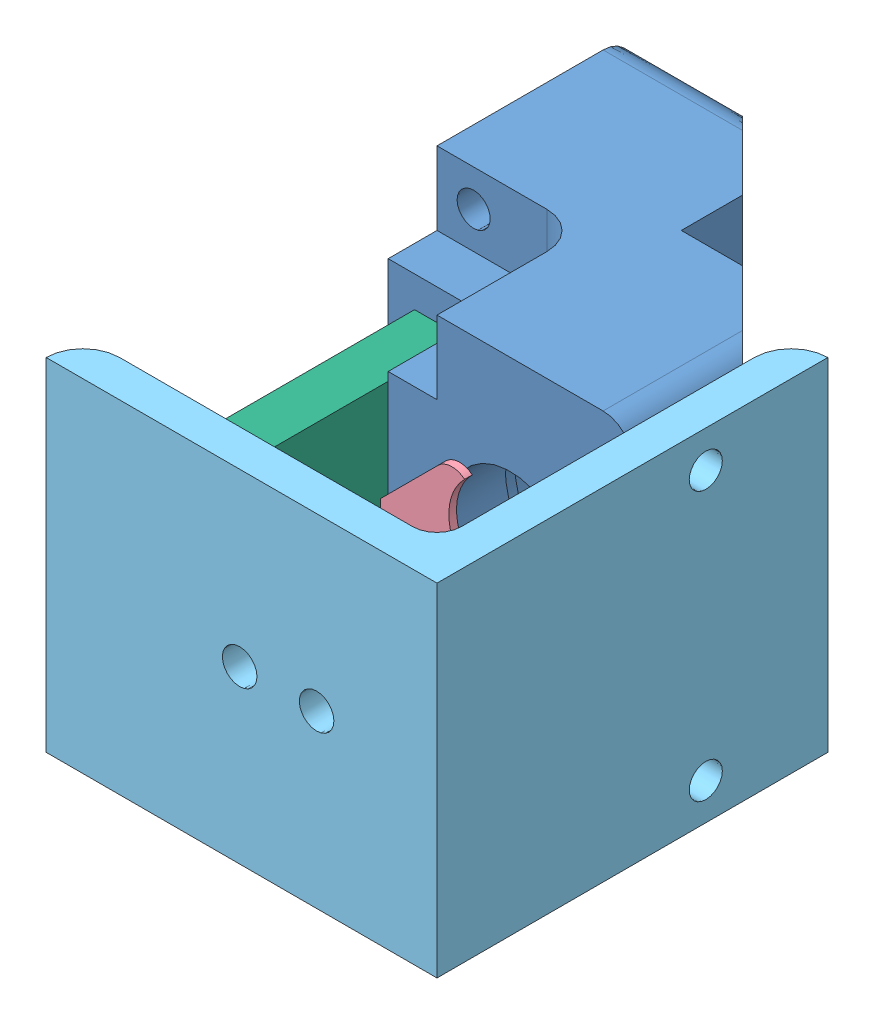
SolidWorks assembly Acceptance Test Adapter, configuration Default. Lengths in mm.
Overall size (87.75 59.75 82.98).
12 component instances, 7 part files, 7 mates.
Components (placement in the parent):
- Subtractive_Thruster Block2-1: Subtractive_Thruster Block2 [Default] at origin size (82.98 59.75 82.98)
  - Subtractive Manifold_V2-1: Subtractive Manifold_V2 [Default] at origin size (44.45 44.45 44.45)
  - C15_212EP10FF_000-1: C15_212EP10FF_000 [Default] at (-7.747 23.8125 -3.175) x (0 -0.840256 0.54219) z (0 -0.54219 -0.840256) size (15 56.18 15)
  - Generic_8-32-1: Generic_8-32 [91251A194] at (-22.1328 15.8201 4.8174) x (0 0 1) z (-1 0 0) size (6.86 6.86 17.41)
  - grainger-36x026-1: grainger-36x026 [Default] at (-10.16 2.7031 -3.175) x (0 -1 0) z (-0.546944 0 0.837169) size (18.47 12.77 12.72)
  - Valve Clip-1: Valve Clip [Default] at (-26.4 -2.5296 23.1671) x (0 0.707107 0.707107) z (0 0.707107 -0.707107) size (18.64 1 15.22)
  - Valve Clip-2: Valve Clip [Default] at (-23.1671 -2.5296 26.4) x (0.707107 -0.707107 0) z (0.707107 0.707107 0) size (18.64 1 15.22)
  - grainger-36x026-2: grainger-36x026 [Default] at (3.175 2.7031 10.16) x (0 -1 0) z (0.837169 0 -0.546944) size (18.47 12.77 12.72)
  - Generic_8-32-2: Generic_8-32 [91251A194] at (-4.8174 15.8201 22.1328) x (-1 0 0) z (0 0 1) size (6.86 6.86 17.41)
  - C15_212EP10FF_000-2: C15_212EP10FF_000 [Default] at (3.175 23.8125 7.747) x (-0.54219 -0.840256 0) z (-0.840256 0.54219 0) size (15 56.18 15)
- Part2^Acceptance Test Adapter-1: Part2^Acceptance Test Adapter [Default] at (23.8252 0 55.5752) x (0 0 -1) z (0 1 0) size (50.8 50.8 44.45) (virtual)
- Part3^Acceptance Test Adapter-1: Part3^Acceptance Test Adapter [Default] at (23.8252 0 50.8) x (0 -1 0) z (0 0 -1) size (25.4 6.35 38.1) (virtual)
Mates (geometry in assembly coordinates):
- Coincident3: coincident anti-aligned: plane of Subtractive_Thruster Block2-1/Subtractive Manifold_V2-1 through (19.05 44.45 11.1125) normal (1 0 0); plane of Part2^Acceptance Test Adapter-1 through (19.05 44.45 47.625) normal (-1 0 0)
- Distance2: distance = 25.4 mm anti-aligned: plane of Part2^Acceptance Test Adapter-1 through (-22.1996 44.45 50.8) normal (0 0 -1); plane of Subtractive_Thruster Block2-1/Subtractive Manifold_V2-1 through (19.05 44.45 25.4) normal (0 0 1)
- Coincident5: coincident aligned: plane of Subtractive_Thruster Block2-1/Subtractive Manifold_V2-1 through (0 0 0) normal (0 -1 0); plane of Part2^Acceptance Test Adapter-1 through (-22.1996 0 55.5752) normal (0 -1 0)
- InPlace1: in place: plane of Part2^Acceptance Test Adapter-1 through (-22.1996 44.45 50.8) normal (0 0 -1); plane of ? through (0 0 50.8) normal (0 0 -1); moOrthogonalPlaneRef_w of Part2^Acceptance Test Adapter-1 through (-22.1996 44.45 50.8) normal (0 0 -1); plane of ? through (0 0 50.8) normal (0 1 0); plane of Part2^Acceptance Test Adapter-1 through (-22.1996 44.45 50.8) normal (0 0 -1); plane of ? through (0 0 50.8) normal (-1 0 0); plane of Part2^Acceptance Test Adapter-1 through (-22.1996 44.45 50.8) normal (0 0 -1); unknown of Part3^Acceptance Test Adapter-1
- Coincident6: coincident aligned: plane of Part2^Acceptance Test Adapter-1; plane of Part3^Acceptance Test Adapter-1
- Coincident7: coincident aligned: moOrthogonalPlaneRef_w of Part2^Acceptance Test Adapter-1 through (23.8252 0 50.8) normal (-1 0 0); plane of Part3^Acceptance Test Adapter-1 through (23.8252 0 50.8) normal (-1 0 0)
- Coincident8: coincident anti-aligned: moOrthogonalPlaneRef_w of Part2^Acceptance Test Adapter-1 through (23.8252 0 50.8) normal (0 1 0); plane of Part3^Acceptance Test Adapter-1 through (23.8252 0 50.8) normal (0 -1 0)
